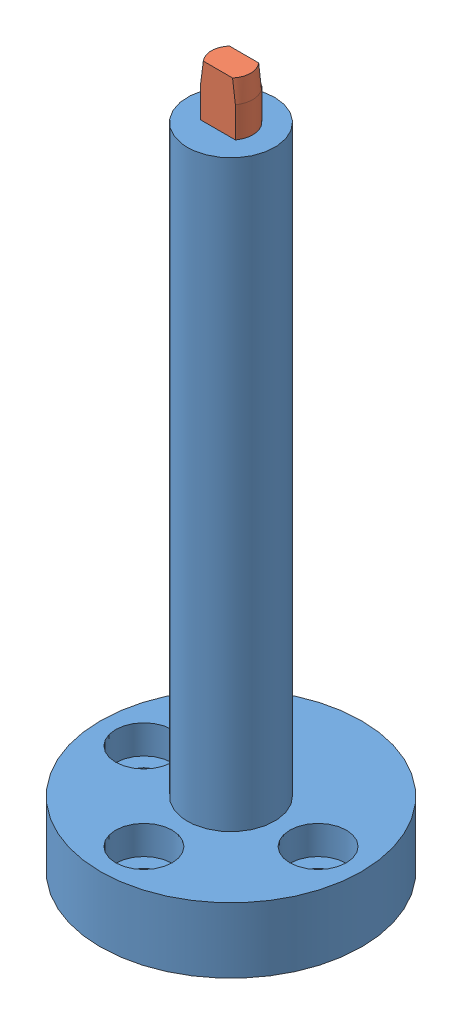
SolidWorks assembly assemb_pino_posi_t1, configuration Default. Lengths in mm.
Overall size (47 161.34 60).
3 component instances, 3 part files, 5 mates.
Components (placement in the parent):
- suporte_posi_t1-1: suporte_posi_t1 [Default] at (55.5939 6.9658 111.8626) size (47 149 60)
- pino_t1-1: pino_t1 [Default] at (55.5939 58.9658 111.8626) x (0 0 1) z (-1 0 0) size (14.5 109 14.5)
- mola_posicionamento-1: mola_posicionamento [Default] at (55.5939 58.9658 111.8626) x (-0.837169 0 -0.546944) z (-0.546944 0 0.837169) size (14.66 52.36 14.64)
Mates (geometry in assembly coordinates):
- Concentric1: concentric anti-aligned: cylinder of suporte_posi_t1-1 through (55.5939 155.9658 111.8626) axis (0 -1 0) radius 10; cylinder of pino_t1-1 through (55.5939 167.9658 111.8626) axis (0 1 0) radius 5
- Coincident1: coincident anti-aligned: plane of suporte_posi_t1-1 through (55.5939 63.9658 111.8626) normal (0 -1 0); plane of pino_t1-1 through (55.5939 63.9658 119.1126) normal (0 1 0)
- Concentric3: concentric aligned: cylinder of suporte_posi_t1-1 through (55.5939 63.9658 111.8626) axis (0 -1 0) radius 7.25; circle of mola_posicionamento-1
- Coincident2: coincident aligned: plane of pino_t1-1 through (55.5939 58.9658 111.8626) normal (0 -1 0); circle of mola_posicionamento-1
- Coincident3: coincident anti-aligned: plane of suporte_posi_t1-1 through (51.5939 155.9658 114.8626) normal (0 0 -1); plane of pino_t1-1 through (59.5939 162.9658 114.8626) normal (0 0 1)
